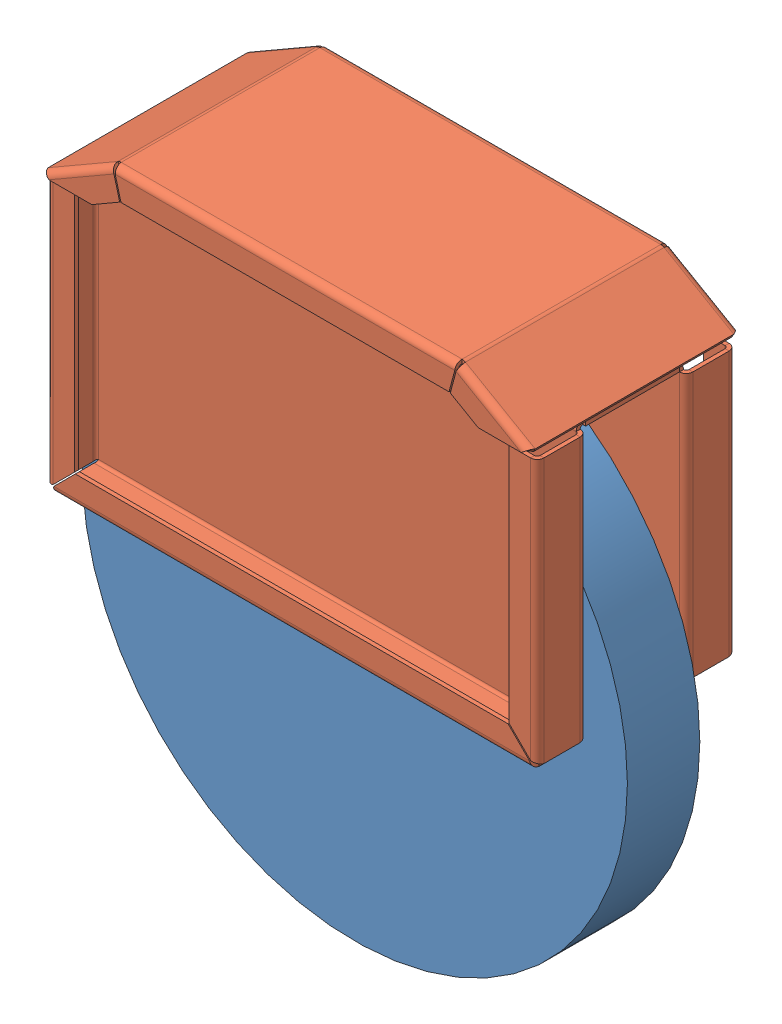
SolidWorks assembly euc0.8, configuration Default. Lengths in mm.
Overall size (490.36 504.65 158.67).
2 component instances, 2 part files, 3 mates.
Components (placement in the parent):
- tire^euc0.8-1: tire^euc0.8 [Default] at (-23.8177 181.0676 4.2847) x (-0.234475 -0.972122 0) z (-0.972122 0.234475 0) size (406.4 53.98 406.4) (virtual)
- chassis_square-1: chassis_square [Default] at (-203.8177 407.2676 68.2722) size (366 239.27 158.67)
Mates (geometry in assembly coordinates):
- Width2: width anti-aligned: plane of tire^euc0.8-1 through (-23.8177 181.0676 58.2597) normal (0 0 1); plane of tire^euc0.8-1 through (-23.8177 181.0676 4.2847) normal (0 0 -1); plane of chassis_square-1 through (-203.8177 407.2676 68.2722) normal (0 0 -1); plane of chassis_square-1 through (-203.8177 407.2676 -5.7278) normal (0 0 1)
- Width4: width: plane of chassis_square-1 through (-206.8177 407.2676 68.2722) normal (-1 0 0); plane of chassis_square-1 through (159.1823 407.2676 68.2722) normal (1 0 0); cylinder of tire^euc0.8-1 through (-23.8177 181.0676 58.2597) axis (0 0 -1) radius 203.2
- Distance1: distance = 20 mm anti-aligned: cylinder of tire^euc0.8-1 through (-23.8177 181.0676 58.2597) axis (0 0 -1) radius 203.2; plane of chassis_square-1 through (-203.8177 404.2676 68.2722) normal (0 -1 0)
